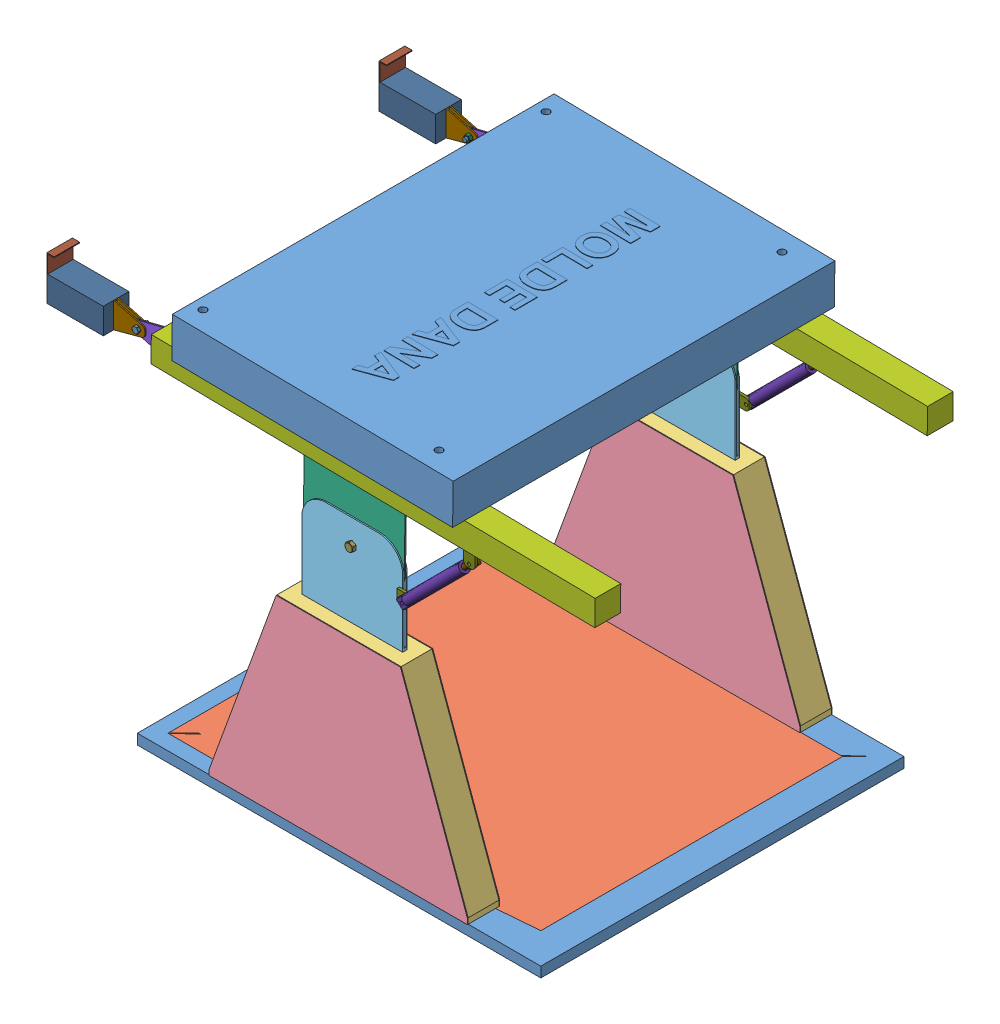
SolidWorks assembly Ensamblaje Mesa de Manejo, configuration Predeterminado. Lengths in mm.
Overall size (1358.89 993.89 946).
39 component instances, 19 part files, 98 mates.
Components (placement in the parent):
- Base mm 1.1-1: Base mm 1.1 [Predeterminado] at (-863.3794 553.217 687.0653) size (1000 25.4 900)
- Lamina mm 1.1-1: Lamina mm 1.1 [Predeterminado] at (-363.3794 576.717 1137.0653) size (923.8 27.3 823.8)
- Base  lateral 1.1-1: Base  lateral 1.1 [Predeterminado] at (-688.3794 578.617 1510.8653) size (640 469.85 76.2)
- Base  lateral 1.1-2: Base  lateral 1.1 [Predeterminado] at (-688.3794 578.617 687.0653) size (640 469.85 76.2)
- lamina lateral 1.1-1: lamina lateral 1.1 [Predeterminado] at (-688.3794 578.617 685.1653) size (640 469.85 1.9)
- lamina lateral 1.1-2: lamina lateral 1.1 [Predeterminado] at (-688.3794 578.617 1587.0653) size (640 469.85 1.9)
- lamina lateral 1.1-3: lamina lateral 1.1 [Predeterminado] at (-688.3794 578.617 763.2653) size (640 469.85 1.9)
- lamina lateral 1.1-4: lamina lateral 1.1 [Predeterminado] at (-688.3794 578.617 1508.9653) size (640 469.85 1.9)
- Base de anclaje de movimiento 1.1-1: Base de anclaje de movimiento 1.1 [Predeterminado] at (-488.3794 1048.4634 1548.6565) size (250 226.35 11)
- Base de anclaje de movimiento 1.1-2: Base de anclaje de movimiento 1.1 [Predeterminado] at (-488.3794 1048.4634 724.8565) size (250 226.35 11)
- Placa movible  1.1-1: Placa movible  1.1 [Predeterminado] at (-489.2657 1156.696 723.5778) x (0.999887 -0.015007 0) z (0 0 1) size (250 220 3.17)
- Placa movible  1.1-2: Placa movible  1.1 [Predeterminado] at (-489.2657 1156.696 1547.3778) x (0.999887 -0.015007 0) z (0 0 1) size (250 220 3.17)
- Ptr 2.5 x 2.5 in-1: Ptr 2.5 x 2.5 in [Predeterminado] at (-834.9718 1445.4165 756.9153) x (0 0 -1) z (0.999887 -0.015007 0) size (63.5 63.5 1100)
- Ptr 2.5 x 2.5 in-2: Ptr 2.5 x 2.5 in [Predeterminado] at (-834.9718 1445.4165 1580.7153) x (0 0 -1) z (0.999887 -0.015007 0) size (63.5 63.5 1100)
- placa de ptr 1.2-1: placa de ptr 1.2 [Predeterminado] at (-835.9248 1381.9236 1547.3778) x (0.999887 -0.015007 0) z (0 0 1) size (77.27 63.5 3.17)
- placa de ptr 1.2-2: placa de ptr 1.2 [Predeterminado] at (-835.9248 1381.9236 723.5778) x (0.999887 -0.015007 0) z (0 0 1) size (77.27 63.5 3.17)
- placa de ptr 1.1-1: placa de ptr 1.1 [Predeterminado] at (-953.9898 1382.8096 1554.9653) x (-1 0 0) z (0 0 -1) size (77.27 63.5 12)
- placa de ptr 1.1-2: placa de ptr 1.1 [Predeterminado] at (-953.9898 1382.8096 731.1653) x (-1 0 0) z (0 0 -1) size (77.27 63.5 12)
- PTR 2.5X2.5 1.2-1: PTR 2.5X2.5 1.2 [Predeterminado] at (-1093.9898 1446.3096 1580.7153) x (0 0 -1) z (1 0 0) size (63.5 63.5 140)
- PTR 2.5X2.5 1.2-2: PTR 2.5X2.5 1.2 [Predeterminado] at (-1093.9898 1446.3096 756.9153) x (0 0 -1) z (1 0 0) size (63.5 63.5 140)
- Placa para detencion-1: Placa para detencion [Predeterminado] at (-1093.9898 1446.3096 1517.2153) size (18 45 63.5)
- Placa para detencion-2: Placa para detencion [Predeterminado] at (-1093.9898 1446.3096 693.4153) size (18 45 63.5)
- Tornillo de 1-2in-1: Tornillo de 1-2in [Predeterminado] at (-363.3794 1214.8134 1563.4653) x (-0.041493 0.999139 0) z (0 0 -1) size (23.87 19 39)
- Tornillo de 1-2in-2: Tornillo de 1-2in [Predeterminado] at (-363.3794 1214.8134 710.6653) size (23.87 19 39)
- Tuerca  1-2in-1: Tuerca  1-2in [Predeterminado] at (-363.3794 1214.8134 730.6653) x (0.61534 0.788262 0) z (0 0 1) size (22.76 18 9)
- Tuerca  1-2in-2: Tuerca  1-2in [Predeterminado] at (-363.3794 1214.8134 1543.4653) x (-1 0 0) z (0 0 -1) size (22.76 18 9)
- tornillo de 3-8in-1: tornillo de 3-8in [Predeterminado] at (-894.7157 1414.5596 712.8153) size (16.34 14.5 31.75)
- tornillo de 3-8in-2: tornillo de 3-8in [Predeterminado] at (-894.7157 1414.5596 1561.3153) x (-1 0 0) z (0 0 -1) size (16.34 14.5 31.75)
- Tuerca de 3-8in-1: Tuerca de 3-8in [Predeterminado] at (-894.7157 1414.5596 1534.4653) x (0 1 0) z (1 0 0) size (16.74 8.5 14.5)
- Tuerca de 3-8in-2: Tuerca de 3-8in [Predeterminado] at (-894.7157 1414.5596 731.1653) x (1 0 0) z (0 -1 0) size (16.74 8.5 14.5)
- Base de sujeción de psiton-1: Base de sujeción de psiton [Predeterminado] at (-61.0121 1370.2933 693.4153) x (0.999887 -0.015007 0) z (0 0 1) size (28 32 6.35)
- Base de sujeción de psiton-2: Base de sujeción de psiton [Predeterminado] at (-246.3794 1156.8134 713.3153) x (0 1 0) z (0 0 1) size (28 32 6.35)
- Base de sujeción de psiton-3: Base de sujeción de psiton [Predeterminado] at (-246.3794 1156.8134 1554.4653) x (0 1 0) z (0 0 1) size (28 32 6.35)
- Base de sujeción de psiton-4: Base de sujeción de psiton [Predeterminado] at (-61.0121 1370.2933 1574.3653) x (0.999887 -0.015007 0) z (0 0 1) size (28 32 6.35)
- Base de piston 1.1-1: Base de piston 1.1 [Predeterminado] at (-228.0319 1165.1522 1566.8153) x (0.706568 0.707645 0) z (0 0 1) size (220 25 25)
- Base de piston 1.1-2: Base de piston 1.1 [Predeterminado] at (-228.0319 1165.1522 707.3153) x (0.706568 0.707645 0) z (0 0 1) size (220 25 25)
- Perno de Piston 1.1-1: Perno de Piston 1.1 [Predeterminado] at (-178.7954 1214.4638 707.3153) x (-0.707645 0.706568 0) z (0.706568 0.707645 0) size (20 12.7 195)
- Perno de Piston 1.1-3: Perno de Piston 1.1 [Predeterminado] at (-178.7954 1214.4638 1566.8153) x (-0.707645 0.706568 0) z (0.706568 0.707645 0) size (20 12.7 195)
- Pieza asema a molde 1.1-1: Pieza asema a molde 1.1 [Predeterminado] at (-754.9709 1444.2158 1610.0653) x (0 0 -1) z (0.999887 -0.015007 0) size (946 101 696)
Mates (geometry in assembly coordinates):
- Ancho1: width aligned: plane of Base mm 1.1-1 through (-863.3794 578.617 687.0653) normal (-1 0 0); plane of Base mm 1.1-1 through (136.6206 578.617 687.0653) normal (1 0 0); plane of Lamina mm 1.1-1 through (-825.2794 578.617 1548.9653) normal (-1 0 0); plane of Lamina mm 1.1-1 through (98.5206 578.617 1548.9653) normal (1 0 0)
- Ancho2: width aligned: plane of Base mm 1.1-1 through (-863.3794 578.617 1587.0653) normal (0 0 1); plane of Base mm 1.1-1 through (-863.3794 578.617 687.0653) normal (0 0 -1); plane of Lamina mm 1.1-1 through (-825.2794 578.617 1548.9653) normal (0 0 1); plane of Lamina mm 1.1-1 through (-825.2794 578.617 725.1653) normal (0 0 -1)
- Coincidente1: coincident aligned: plane of Base mm 1.1-1 through (-863.3794 578.617 687.0653) normal (0 1 0); plane of Lamina mm 1.1-1 through (-363.3794 578.617 1137.0653) normal (0 1 0)
- Coincidente2: coincident anti-aligned: plane of Base mm 1.1-1 through (-863.3794 578.617 687.0653) normal (0 1 0); plane of Base  lateral 1.1-1 through (-688.3794 578.617 1587.0653) normal (0 -1 0)
- Coincidente3: coincident aligned: plane of Base mm 1.1-1 through (-863.3794 578.617 1587.0653) normal (0 0 1); plane of Base  lateral 1.1-1 through (-688.3794 578.617 1587.0653) normal (0 0 1)
- Ancho3: width aligned: plane of Base mm 1.1-1 through (136.6206 578.617 687.0653) normal (1 0 0); plane of Base mm 1.1-1 through (-863.3794 578.617 687.0653) normal (-1 0 0); plane of Base  lateral 1.1-1 through (-43.3794 654.817 1587.0653) normal (1 0 0); plane of Base  lateral 1.1-1 through (-683.3794 654.817 1587.0653) normal (-1 0 0)
- Coincidente4: coincident anti-aligned: plane of Base mm 1.1-1 through (-863.3794 578.617 687.0653) normal (0 1 0); plane of Base  lateral 1.1-2 through (-688.3794 578.617 763.2653) normal (0 -1 0)
- Coincidente5: coincident aligned: plane of Base mm 1.1-1 through (-863.3794 578.617 687.0653) normal (0 0 -1); plane of Base  lateral 1.1-2 through (-688.3794 578.617 687.0653) normal (0 0 -1)
- Ancho4: width aligned: plane of Base mm 1.1-1 through (136.6206 578.617 687.0653) normal (1 0 0); plane of Base mm 1.1-1 through (-863.3794 578.617 687.0653) normal (-1 0 0); plane of Base  lateral 1.1-2 through (-43.3794 654.817 763.2653) normal (1 0 0); plane of Base  lateral 1.1-2 through (-683.3794 654.817 763.2653) normal (-1 0 0)
- Coincidente6: coincident anti-aligned: plane of Base  lateral 1.1-2 through (-688.3794 578.617 687.0653) normal (0 0 -1); plane of lamina lateral 1.1-1 through (-688.3794 578.617 687.0653) normal (0 0 1)
- Coincidente7: coincident aligned: plane of Base  lateral 1.1-2 through (-517.3693 1048.4634 763.2653) normal (0 1 0); plane of lamina lateral 1.1-1 through (-517.3693 1048.4634 687.0653) normal (0 1 0)
- Coincidente8: coincident aligned: line of Base  lateral 1.1-2 through (-209.3894 1048.4634 763.2653) axis (0 0 -1); line of lamina lateral 1.1-1 through (-209.3894 1048.4634 687.0653) axis (0 0 -1)
- Coincidente9: coincident anti-aligned: plane of Base  lateral 1.1-1 through (-688.3794 578.617 1587.0653) normal (0 0 1); plane of lamina lateral 1.1-2 through (-688.3794 578.617 1587.0653) normal (0 0 -1)
- Coincidente10: coincident aligned: plane of Base  lateral 1.1-1 through (-517.3693 1048.4634 1587.0653) normal (0 1 0); plane of lamina lateral 1.1-2 through (-517.3693 1048.4634 1588.9653) normal (0 1 0)
- Coincidente11: coincident aligned: line of Base  lateral 1.1-1 through (-517.3693 1048.4634 1587.0653) axis (0 0 -1); line of lamina lateral 1.1-2 through (-517.3693 1048.4634 1588.9653) axis (0 0 -1)
- Coincidente12: coincident anti-aligned: plane of Base  lateral 1.1-2 through (-688.3794 578.617 763.2653) normal (0 0 1); plane of lamina lateral 1.1-3 through (-688.3794 578.617 763.2653) normal (0 0 -1)
- Coincidente13: coincident aligned: plane of Base  lateral 1.1-2 through (-517.3693 1048.4634 763.2653) normal (0 1 0); plane of lamina lateral 1.1-3 through (-517.3693 1048.4634 765.1653) normal (0 1 0)
- Coincidente14: coincident aligned: line of Base  lateral 1.1-2 through (-517.3693 1048.4634 763.2653) axis (0 0 -1); line of lamina lateral 1.1-3 through (-517.3693 1048.4634 765.1653) axis (0 0 -1)
- Coincidente15: coincident anti-aligned: plane of Base  lateral 1.1-1 through (-688.3794 578.617 1510.8653) normal (0 0 -1); plane of lamina lateral 1.1-4 through (-688.3794 578.617 1510.8653) normal (0 0 1)
- Coincidente16: coincident aligned: plane of Base  lateral 1.1-1 through (-517.3693 1048.4634 1587.0653) normal (0 1 0); plane of lamina lateral 1.1-4 through (-517.3693 1048.4634 1510.8653) normal (0 1 0)
- Coincidente17: coincident aligned: line of Base  lateral 1.1-1 through (-517.3693 1048.4634 1587.0653) axis (0 0 -1); line of lamina lateral 1.1-4 through (-517.3693 1048.4634 1510.8653) axis (0 0 -1)
- Coincidente18: coincident anti-aligned: plane of Base  lateral 1.1-1 through (-517.3693 1048.4634 1587.0653) normal (0 1 0); plane of Base de anclaje de movimiento 1.1-1 through (-488.3794 1048.4634 1548.6565) normal (0 -1 0)
- Ancho5: width aligned: plane of Base  lateral 1.1-1 through (-688.3794 578.617 1587.0653) normal (0 0 1); plane of Base  lateral 1.1-1 through (-688.3794 578.617 1510.8653) normal (0 0 -1); plane of Base de anclaje de movimiento 1.1-1 through (-488.3794 1054.8134 1554.4653) normal (0 0 1); plane of Base de anclaje de movimiento 1.1-1 through (-488.3794 1054.8134 1543.4653) normal (0 0 -1)
- Ancho6: width aligned: plane of Base  lateral 1.1-1 through (-683.3794 654.817 1587.0653) normal (-1 0 0); plane of Base  lateral 1.1-1 through (-43.3794 654.817 1587.0653) normal (1 0 0); plane of Base de anclaje de movimiento 1.1-1 through (-488.3794 1054.8134 1543.4653) normal (-1 0 0); plane of Base de anclaje de movimiento 1.1-1 through (-238.3794 1054.8134 1543.4653) normal (1 0 0)
- Coincidente19: coincident anti-aligned: plane of Base  lateral 1.1-2 through (-517.3693 1048.4634 763.2653) normal (0 1 0); plane of Base de anclaje de movimiento 1.1-2 through (-488.3794 1048.4634 724.8565) normal (0 -1 0)
- Ancho7: width aligned: plane of Base  lateral 1.1-2 through (-688.3794 578.617 687.0653) normal (0 0 -1); plane of Base  lateral 1.1-2 through (-688.3794 578.617 763.2653) normal (0 0 1); plane of Base de anclaje de movimiento 1.1-2 through (-488.3794 1054.8134 719.6653) normal (0 0 -1); plane of Base de anclaje de movimiento 1.1-2 through (-488.3794 1054.8134 730.6653) normal (0 0 1)
- Ancho8: width aligned: plane of Base  lateral 1.1-2 through (-683.3794 654.817 763.2653) normal (-1 0 0); plane of Base  lateral 1.1-2 through (-43.3794 654.817 763.2653) normal (1 0 0); plane of Base de anclaje de movimiento 1.1-2 through (-488.3794 1054.8134 719.6653) normal (-1 0 0); plane of Base de anclaje de movimiento 1.1-2 through (-238.3794 1054.8134 719.6653) normal (1 0 0)
- Ancho9: width aligned: plane of Base de anclaje de movimiento 1.1-2 through (-488.3794 1054.8134 730.6653) normal (0 0 1); plane of Base de anclaje de movimiento 1.1-2 through (-488.3794 1054.8134 719.6653) normal (0 0 -1); plane of Placa movible  1.1-1 through (-489.2657 1156.696 726.7528) normal (0 0 1); plane of Placa movible  1.1-1 through (-489.2657 1156.696 723.5778) normal (0 0 -1)
- Concéntrica1: concentric anti-aligned: cylinder of Base de anclaje de movimiento 1.1-2 through (-363.3794 1214.8134 748.6258) axis (0 0 -1) radius 6.35; cylinder of Placa movible  1.1-1 through (-363.3794 1214.8134 720.4028) axis (0 0 1) radius 6.35
- Ancho10: width aligned: plane of Base de anclaje de movimiento 1.1-1 through (-488.3794 1054.8134 1554.4653) normal (0 0 1); plane of Base de anclaje de movimiento 1.1-1 through (-488.3794 1054.8134 1543.4653) normal (0 0 -1); plane of Placa movible  1.1-2 through (-489.2657 1156.696 1550.5528) normal (0 0 1); plane of Placa movible  1.1-2 through (-489.2657 1156.696 1547.3778) normal (0 0 -1)
- Concéntrica2: concentric anti-aligned: cylinder of Base de anclaje de movimiento 1.1-1 through (-363.3794 1214.8134 1572.4258) axis (0 0 -1) radius 6.35; cylinder of Placa movible  1.1-2 through (-363.3794 1214.8134 1544.2028) axis (0 0 1) radius 6.35
- Coincidente20: coincident anti-aligned: plane of Placa movible  1.1-1 through (-485.9642 1376.6712 726.7528) normal (0.015007 0.999887 0); plane of Ptr 2.5 x 2.5 in-1 through (263.9513 1365.416 756.9153) normal (-0.015007 -0.999887 0)
- Ancho11: width aligned: plane of Ptr 2.5 x 2.5 in-1 through (264.9043 1428.9089 693.4153) normal (0 0 -1); plane of Ptr 2.5 x 2.5 in-1 through (264.9043 1428.9089 756.9153) normal (0 0 1); plane of Placa movible  1.1-1 through (-489.2657 1156.696 723.5778) normal (0 0 -1); plane of Placa movible  1.1-1 through (-489.2657 1156.696 726.7528) normal (0 0 1)
- Coincidente21: coincident anti-aligned: plane of Placa movible  1.1-2 through (-485.9642 1376.6712 1550.5528) normal (0.015007 0.999887 0); plane of Ptr 2.5 x 2.5 in-2 through (263.9513 1365.416 1580.7153) normal (-0.015007 -0.999887 0)
- Ancho12: width aligned: plane of Ptr 2.5 x 2.5 in-2 through (264.9043 1428.9089 1517.2153) normal (0 0 -1); plane of Ptr 2.5 x 2.5 in-2 through (264.9043 1428.9089 1580.7153) normal (0 0 1); plane of Placa movible  1.1-2 through (-489.2657 1156.696 1547.3778) normal (0 0 -1); plane of Placa movible  1.1-2 through (-489.2657 1156.696 1550.5528) normal (0 0 1)
- Distancia1: distance = 500 mm aligned: plane of Placa movible  1.1-2 through (-239.2939 1152.9443 1550.5528) normal (0.999887 -0.015007 0); plane of Ptr 2.5 x 2.5 in-2 through (264.9043 1428.9089 1580.7153) normal (0.999887 -0.015007 0)
- Coincidente22: coincident aligned: plane of Ptr 2.5 x 2.5 in-1 through (264.9043 1428.9089 756.9153) normal (0.999887 -0.015007 0); plane of Ptr 2.5 x 2.5 in-2 through (264.9043 1428.9089 1580.7153) normal (0.999887 -0.015007 0)
- Ancho13: width aligned: plane of Ptr 2.5 x 2.5 in-2 through (264.9043 1428.9089 1517.2153) normal (0 0 -1); plane of Ptr 2.5 x 2.5 in-2 through (264.9043 1428.9089 1580.7153) normal (0 0 1); plane of placa de ptr 1.2-1 through (-835.9248 1381.9236 1547.3778) normal (0 0 -1); plane of placa de ptr 1.2-1 through (-835.9248 1381.9236 1550.5528) normal (0 0 1)
- Coincidente23: coincident anti-aligned: plane of Ptr 2.5 x 2.5 in-2 through (-834.9718 1445.4165 1580.7153) normal (-0.999887 0.015007 0); plane of placa de ptr 1.2-1 through (-835.9248 1381.9236 1550.5528) normal (0.999887 -0.015007 0)
- Coincidente24: coincident: plane of Ptr 2.5 x 2.5 in-2 through (264.9043 1428.9089 1580.7153) normal (0.015007 0.999887 0); line of placa de ptr 1.2-1 through (-834.9718 1445.4165 1550.5528) axis (0 0 -1)
- Ancho14: width aligned: plane of Ptr 2.5 x 2.5 in-1 through (264.9043 1428.9089 756.9153) normal (0 0 1); plane of Ptr 2.5 x 2.5 in-1 through (264.9043 1428.9089 693.4153) normal (0 0 -1); plane of placa de ptr 1.2-2 through (-835.9248 1381.9236 726.7528) normal (0 0 1); plane of placa de ptr 1.2-2 through (-835.9248 1381.9236 723.5778) normal (0 0 -1)
- Coincidente25: coincident anti-aligned: plane of Ptr 2.5 x 2.5 in-1 through (-834.9718 1445.4165 756.9153) normal (-0.999887 0.015007 0); plane of placa de ptr 1.2-2 through (-835.9248 1381.9236 726.7528) normal (0.999887 -0.015007 0)
- Coincidente26: coincident anti-aligned: line of Ptr 2.5 x 2.5 in-1 through (-834.9718 1445.4165 693.4153) axis (0 0 1); line of placa de ptr 1.2-2 through (-834.9718 1445.4165 726.7528) axis (0 0 -1)
- Ancho15: width aligned: plane of placa de ptr 1.1-1 through (-953.9898 1382.8096 1554.9653) normal (0 0 1); plane of placa de ptr 1.1-1 through (-953.9898 1382.8096 1542.9653) normal (0 0 -1); plane of placa de ptr 1.2-1 through (-835.9248 1381.9236 1550.5528) normal (0 0 1); plane of placa de ptr 1.2-1 through (-835.9248 1381.9236 1547.3778) normal (0 0 -1)
- Concéntrica3: concentric anti-aligned: cylinder of placa de ptr 1.2-1 through (-894.7157 1414.5596 1547.3778) axis (0 0 1) radius 4.7625; cylinder of placa de ptr 1.1-1 through (-894.7157 1414.5596 1568.4357) axis (0 0 -1) radius 4.7625
- Ancho16: width aligned: plane of placa de ptr 1.1-2 through (-953.9898 1382.8096 719.1653) normal (0 0 -1); plane of placa de ptr 1.1-2 through (-953.9898 1382.8096 731.1653) normal (0 0 1); plane of placa de ptr 1.2-2 through (-835.9248 1381.9236 723.5778) normal (0 0 -1); plane of placa de ptr 1.2-2 through (-835.9248 1381.9236 726.7528) normal (0 0 1)
- Concéntrica4: concentric anti-aligned: cylinder of placa de ptr 1.2-2 through (-894.7157 1414.5596 723.5778) axis (0 0 1) radius 4.7625; cylinder of placa de ptr 1.1-2 through (-894.7157 1414.5596 744.6357) axis (0 0 -1) radius 4.7625
- Ancho17: width aligned: plane of PTR 2.5X2.5 1.2-1 through (-953.9898 1446.3096 1580.7153) normal (0 0 1); plane of PTR 2.5X2.5 1.2-1 through (-953.9898 1446.3096 1517.2153) normal (0 0 -1); plane of placa de ptr 1.1-1 through (-953.9898 1382.8096 1554.9653) normal (0 0 1); plane of placa de ptr 1.1-1 through (-953.9898 1382.8096 1542.9653) normal (0 0 -1)
- Coincidente27: coincident anti-aligned: plane of placa de ptr 1.1-1 through (-953.9898 1382.8096 1542.9653) normal (-1 0 0); plane of PTR 2.5X2.5 1.2-1 through (-953.9898 1446.3096 1580.7153) normal (1 0 0)
- Coincidente28: coincident: line of placa de ptr 1.1-1 through (-953.9898 1446.3096 1542.9653) axis (0 0 1); plane of PTR 2.5X2.5 1.2-1 through (-953.9898 1446.3096 1580.7153) normal (0 1 0)
- Ancho18: width aligned: plane of PTR 2.5X2.5 1.2-2 through (-953.9898 1446.3096 756.9153) normal (0 0 1); plane of PTR 2.5X2.5 1.2-2 through (-953.9898 1446.3096 693.4153) normal (0 0 -1); plane of placa de ptr 1.1-2 through (-953.9898 1382.8096 731.1653) normal (0 0 1); plane of placa de ptr 1.1-2 through (-953.9898 1382.8096 719.1653) normal (0 0 -1)
- Coincidente29: coincident anti-aligned: plane of placa de ptr 1.1-2 through (-953.9898 1382.8096 719.1653) normal (-1 0 0); plane of PTR 2.5X2.5 1.2-2 through (-953.9898 1446.3096 756.9153) normal (1 0 0)
- Coincidente30: coincident aligned: line of placa de ptr 1.1-2 through (-953.9898 1446.3096 719.1653) axis (0 0 1); line of PTR 2.5X2.5 1.2-2 through (-953.9898 1446.3096 693.4153) axis (0 0 1)
- Coincidente31: coincident aligned: plane of PTR 2.5X2.5 1.2-1 through (-953.9898 1446.3096 1580.7153) normal (0 1 0); plane of PTR 2.5X2.5 1.2-2 through (-953.9898 1446.3096 756.9153) normal (0 1 0)
- Coincidente32: coincident anti-aligned: plane of PTR 2.5X2.5 1.2-1 through (-953.9898 1446.3096 1580.7153) normal (0 1 0); plane of Placa para detencion-1 through (-1092.0898 1446.3096 1580.7153) normal (0 -1 0)
- Coincidente33: coincident aligned: plane of PTR 2.5X2.5 1.2-1 through (-1093.9898 1446.3096 1580.7153) normal (-1 0 0); plane of Placa para detencion-1 through (-1093.9898 1446.3096 1580.7153) normal (-1 0 0)
- Coincidente34: coincident aligned: plane of PTR 2.5X2.5 1.2-1 through (-953.9898 1446.3096 1580.7153) normal (0 0 1); plane of Placa para detencion-1 through (-1093.9898 1446.3096 1580.7153) normal (0 0 1)
- Coincidente35: coincident anti-aligned: plane of PTR 2.5X2.5 1.2-2 through (-953.9898 1446.3096 756.9153) normal (0 1 0); plane of Placa para detencion-2 through (-1092.0898 1446.3096 756.9153) normal (0 -1 0)
- Coincidente36: coincident aligned: plane of PTR 2.5X2.5 1.2-2 through (-1093.9898 1446.3096 756.9153) normal (-1 0 0); plane of Placa para detencion-2 through (-1093.9898 1446.3096 756.9153) normal (-1 0 0)
- Coincidente37: coincident aligned: plane of PTR 2.5X2.5 1.2-2 through (-953.9898 1446.3096 756.9153) normal (0 0 1); plane of Placa para detencion-2 through (-1093.9898 1446.3096 756.9153) normal (0 0 1)
- Concéntrica5: concentric anti-aligned: cylinder of Base de anclaje de movimiento 1.1-1 through (-363.3794 1214.8134 1572.4258) axis (0 0 -1) radius 6.35; cylinder of Tornillo de 1-2in-1 through (-363.3794 1214.8134 1524.4653) axis (0 0 1) radius 6.35
- Coincidente38: coincident anti-aligned: plane of Base de anclaje de movimiento 1.1-1 through (-488.3794 1054.8134 1554.4653) normal (0 0 1); plane of Tornillo de 1-2in-1 through (-363.3794 1214.8134 1554.4653) normal (0 0 -1)
- Concéntrica6: concentric aligned: cylinder of Base de anclaje de movimiento 1.1-2 through (-363.3794 1214.8134 748.6258) axis (0 0 -1) radius 6.35; cylinder of Tornillo de 1-2in-2 through (-363.3794 1214.8134 749.6653) axis (0 0 -1) radius 6.35
- Coincidente39: coincident anti-aligned: plane of Base de anclaje de movimiento 1.1-2 through (-488.3794 1054.8134 719.6653) normal (0 0 -1); plane of Tornillo de 1-2in-2 through (-363.3794 1214.8134 719.6653) normal (0 0 1)
- Concéntrica7: concentric aligned: cylinder of Tornillo de 1-2in-2 through (-363.3794 1214.8134 749.6653) axis (0 0 -1) radius 6.35; cylinder of Tuerca  1-2in-1 through (-363.3794 1214.8134 739.6653) axis (0 0 -1) radius 6.35
- Coincidente40: coincident anti-aligned: plane of Base de anclaje de movimiento 1.1-2 through (-488.3794 1054.8134 730.6653) normal (0 0 1); plane of Tuerca  1-2in-1 through (-363.3794 1214.8134 730.6653) normal (0 0 -1)
- Concéntrica8: concentric aligned: cylinder of Tornillo de 1-2in-1 through (-363.3794 1214.8134 1524.4653) axis (0 0 1) radius 6.35; cylinder of Tuerca  1-2in-2 through (-363.3794 1214.8134 1534.4653) axis (0 0 1) radius 6.35
- Coincidente41: coincident anti-aligned: plane of Base de anclaje de movimiento 1.1-1 through (-488.3794 1054.8134 1543.4653) normal (0 0 -1); plane of Tuerca  1-2in-2 through (-363.3794 1214.8134 1543.4653) normal (0 0 1)
- Concéntrica9: concentric aligned: cylinder of placa de ptr 1.1-2 through (-894.7157 1414.5596 744.6357) axis (0 0 -1) radius 4.7625; cylinder of tornillo de 3-8in-1 through (-894.7157 1414.5596 744.5653) axis (0 0 -1) radius 4.7625
- Coincidente42: coincident anti-aligned: plane of placa de ptr 1.1-2 through (-953.9898 1382.8096 719.1653) normal (0 0 -1); plane of tornillo de 3-8in-1 through (-894.7157 1414.5596 719.1653) normal (0 0 1)
- Concéntrica10: concentric anti-aligned: cylinder of placa de ptr 1.1-1 through (-894.7157 1414.5596 1568.4357) axis (0 0 -1) radius 4.7625; cylinder of tornillo de 3-8in-2 through (-894.7157 1414.5596 1529.5653) axis (0 0 1) radius 4.7625
- Coincidente43: coincident anti-aligned: plane of placa de ptr 1.1-1 through (-953.9898 1382.8096 1554.9653) normal (0 0 1); plane of tornillo de 3-8in-2 through (-894.7157 1414.5596 1554.9653) normal (0 0 -1)
- Concéntrica11: concentric anti-aligned: cylinder of tornillo de 3-8in-2 through (-894.7157 1414.5596 1529.5653) axis (0 0 1) radius 4.7625; cylinder of Tuerca de 3-8in-1 through (-894.7157 1414.5596 1542.9653) axis (0 0 -1) radius 5
- Coincidente44: coincident anti-aligned: plane of placa de ptr 1.1-1 through (-953.9898 1382.8096 1542.9653) normal (0 0 -1); plane of Tuerca de 3-8in-1 through (-894.7157 1414.5596 1542.9653) normal (0 0 1)
- Concéntrica12: concentric aligned: cylinder of tornillo de 3-8in-1 through (-894.7157 1414.5596 744.5653) axis (0 0 -1) radius 4.7625; cylinder of Tuerca de 3-8in-2 through (-894.7157 1414.5596 739.6653) axis (0 0 -1) radius 5
- Coincidente45: coincident anti-aligned: plane of placa de ptr 1.1-2 through (-953.9898 1382.8096 731.1653) normal (0 0 1); plane of Tuerca de 3-8in-2 through (-894.7157 1414.5596 731.1653) normal (0 0 -1)
- Coincidente46: coincident aligned: plane of Ptr 2.5 x 2.5 in-1 through (264.9043 1428.9089 693.4153) normal (0 0 -1); plane of Base de sujeción de psiton-1 through (-61.0121 1370.2933 693.4153) normal (0 0 -1)
- Coincidente47: coincident anti-aligned: plane of Ptr 2.5 x 2.5 in-1 through (263.9513 1365.416 756.9153) normal (-0.015007 -0.999887 0); plane of Base de sujeción de psiton-1 through (-61.0121 1370.2933 699.7653) normal (0.015007 0.999887 0)
- Coincidente48: coincident anti-aligned: plane of Base de anclaje de movimiento 1.1-2 through (-488.3794 1054.8134 719.6653) normal (0 0 -1); plane of Base de sujeción de psiton-2 through (-246.3794 1156.8134 719.6653) normal (0 0 1)
- Distancia2: distance = 8 mm anti-aligned: plane of Base de sujeción de psiton-2 through (-246.3794 1156.8134 719.6653) normal (-1 0 0); plane of Base de anclaje de movimiento 1.1-2 through (-238.3794 1054.8134 719.6653) normal (1 0 0)
- Distancia3: distance = 90 mm aligned: plane of Base de anclaje de movimiento 1.1-2 through (-488.3794 1274.8134 724.8565) normal (0 1 0); plane of Base de sujeción de psiton-2 through (-246.3794 1184.8134 719.6653) normal (0 1 0)
- Distancia4: distance = 175 mm anti-aligned: plane of Placa movible  1.1-1 through (-239.2939 1152.9443 726.7528) normal (0.999887 -0.015007 0); plane of Base de sujeción de psiton-1 through (-61.0121 1370.2933 699.7653) normal (-0.999887 0.015007 0)
- Coincidente49: coincident anti-aligned: plane of Base de anclaje de movimiento 1.1-1 through (-488.3794 1054.8134 1554.4653) normal (0 0 1); plane of Base de sujeción de psiton-3 through (-246.3794 1156.8134 1554.4653) normal (0 0 -1)
- Coincidente50: coincident aligned: plane of Base de sujeción de psiton-2 through (-246.3794 1184.8134 719.6653) normal (0 1 0); plane of Base de sujeción de psiton-3 through (-246.3794 1184.8134 1560.8153) normal (0 1 0)
- Coincidente51: coincident aligned: plane of Base de sujeción de psiton-2 through (-214.3794 1156.8134 719.6653) normal (1 0 0); plane of Base de sujeción de psiton-3 through (-214.3794 1156.8134 1560.8153) normal (1 0 0)
- Coincidente52: coincident aligned: plane of Ptr 2.5 x 2.5 in-2 through (264.9043 1428.9089 1580.7153) normal (0 0 1); plane of Base de sujeción de psiton-4 through (-61.0121 1370.2933 1580.7153) normal (0 0 1)
- Coincidente53: coincident anti-aligned: plane of Ptr 2.5 x 2.5 in-2 through (263.9513 1365.416 1580.7153) normal (-0.015007 -0.999887 0); plane of Base de sujeción de psiton-4 through (-61.0121 1370.2933 1580.7153) normal (0.015007 0.999887 0)
- Coincidente54: coincident aligned: plane of Base de sujeción de psiton-1 through (-33.0152 1369.8731 699.7653) normal (0.999887 -0.015007 0); plane of Base de sujeción de psiton-4 through (-33.0152 1369.8731 1580.7153) normal (0.999887 -0.015007 0)
- Concéntrica13: concentric anti-aligned: cylinder of Base de sujeción de psiton-3 through (-222.3794 1170.8134 1560.8153) axis (0 0 -1) radius 3.9688; cylinder of Base de piston 1.1-1 through (-222.3794 1170.8134 1550.8153) axis (0 0 1) radius 3.9688
- Coincidente55: coincident anti-aligned: plane of Base de sujeción de psiton-3 through (-246.3794 1156.8134 1560.8153) normal (0 0 1); plane of Base de piston 1.1-1 through (-222.8481 1191.0653 1560.8153) normal (0 0 -1)
- Concéntrica14: concentric anti-aligned: cylinder of Base de sujeción de psiton-2 through (-222.3794 1170.8134 719.6653) axis (0 0 -1) radius 3.9688; cylinder of Base de piston 1.1-2 through (-222.3794 1170.8134 691.3153) axis (0 0 1) radius 3.9688
- Coincidente56: coincident anti-aligned: plane of Base de sujeción de psiton-2 through (-246.3794 1156.8134 713.3153) normal (0 0 -1); plane of Base de piston 1.1-2 through (-202.6776 1170.9255 713.3153) normal (0 0 1)
- Concéntrica15: concentric aligned: cylinder of Base de sujeción de psiton-1 through (-47.3738 1346.0859 699.7653) axis (0 0 -1) radius 3.9688; cylinder of Perno de Piston 1.1-1 through (-47.3738 1346.0859 733.3153) axis (0 0 -1) radius 3.9688
- Concéntrica16: concentric anti-aligned: cylinder of Base de piston 1.1-2 through (-171.5065 1221.7638 707.3153) axis (0.706568 0.707645 0) radius 6.35; cylinder of Perno de Piston 1.1-1 through (-62.2117 1331.2253 707.3153) axis (-0.706568 -0.707645 0) radius 6.35
- Concéntrica19: concentric aligned: cylinder of Base de sujeción de psiton-4 through (-47.3738 1346.0859 1580.7153) axis (0 0 -1) radius 3.9688; cylinder of Perno de Piston 1.1-3 through (-47.3738 1346.0859 1592.8153) axis (0 0 -1) radius 3.9688
- Concéntrica20: concentric anti-aligned: cylinder of Base de piston 1.1-1 through (-171.5065 1221.7638 1566.8153) axis (0.706568 0.707645 0) radius 6.35; cylinder of Perno de Piston 1.1-3 through (-62.2117 1331.2253 1566.8153) axis (-0.706568 -0.707645 0) radius 6.35
- Coincidente57: coincident anti-aligned: plane of Ptr 2.5 x 2.5 in-2 through (264.9043 1428.9089 1580.7153) normal (0.015007 0.999887 0); plane of Pieza asema a molde 1.1-1 through (-754.9709 1444.2158 1610.0653) normal (-0.015007 -0.999887 0)
- Ancho19: width aligned: plane of Pieza asema a molde 1.1-1 through (-753.4702 1544.2045 1610.0653) normal (0 0 1); plane of Pieza asema a molde 1.1-1 through (-753.4702 1544.2045 664.0653) normal (0 0 -1); plane of Ptr 2.5 x 2.5 in-2 through (264.9043 1428.9089 1580.7153) normal (0 0 1); plane of Ptr 2.5 x 2.5 in-1 through (264.9043 1428.9089 693.4153) normal (0 0 -1)
